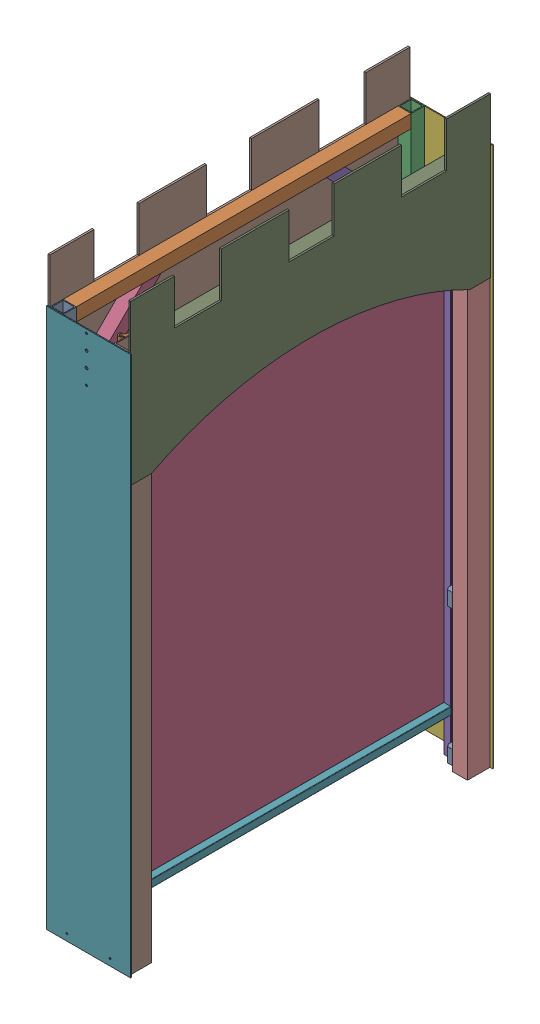
SolidWorks assembly GE-16160_ASM, configuration Default. Lengths in mm.
Overall size (285.75 1981.41 1229.61).
28 component instances, 13 part files, 0 mates.
Components (placement in the parent):
- GE-16161_ASM-1: GE-16161_ASM [Default] at origin size (44.45 1828.8 1223.26)
  - GE-16161-01-1: GE-16161-01 [Default] at origin size (44.45 1828.8 44.45)
  - GE-16161-02-1: GE-16161-02 [Default] at (-22.225 1784.35 -1156.589) size (44.45 44.45 1134.36)
  - GE-16161-01-2: GE-16161-01 [Default] at (0 0 -1178.814) x (-1 0 0) z (0 0 -1) size (44.45 1828.8 44.45)
  - GE-16161-03-1: GE-16161-03 [Default] at (-22.225 1784.35 -246.7314) x (1 0 0) z (0 0.707107 -0.707107) size (44.45 44.45 406.4)
  - GE-16161-03-2: GE-16161-03 [Default] at (-22.225 1559.8436 -1156.589) x (1 0 0) z (0 -0.707107 -0.707107) size (44.45 44.45 406.4)
- GE-16163-1: GE-16163 [Default] at (111.125 914.4 -1201.039) x (0 0 -1) z (0 -1 0) size (3.17 285.75 1828.8)
- GE-16163-2: GE-16163 [Default] at (111.125 914.4 22.225) x (0 0 1) z (0 -1 0) size (3.17 285.75 1828.8)
- GE-16162_ASM-1: GE-16162_ASM [Default] at (219.075 0 -15.875) size (50.8 1828.8 1223.26)
  - GE-16162-01-1: GE-16162-01 [Default] at origin size (50.8 1828.8 76.2)
  - GE-16162-02-1: GE-16162-02 [Default] at (-19.05 1784.35 -1108.964) size (44.45 44.45 1070.86)
  - GE-16162-01-2: GE-16162-01 [Default] at (0 0 -1147.064) x (-1 0 0) z (0 0 -1) size (50.8 1828.8 76.2)
  - GE-16162-03-1: GE-16162-03 [Default] at (-19.05 1559.8436 -38.1) x (1 0 0) z (0 0.707107 -0.707107) size (44.45 44.45 406.4)
  - GE-16162-03-2: GE-16162-03 [Default] at (-19.05 1784.35 -884.4576) x (1 0 0) z (0 -0.707107 -0.707107) size (44.45 44.45 406.4)
- GE-16164-1: GE-16164 [Default] at (193.675 -0.2 -1134.364) x (0 0 1) z (-1 0 0) size (37 1829.02 22)
- GE-16164-2: GE-16164 [Default] at (193.675 1828.8 -44.45) x (0 0 -1) z (-1 0 0) size (37 1829.02 22)
- GE-16165_ASM-1: GE-16165_ASM [Default] at (139.975 1571.625 -17.85) x (-1 0 0) z (0 -1 0) size (68.08 1193.8 1584.33)
  - GE-16166-01-1: GE-16166-01 [Default] at origin size (25.4 1143 25.4)
  - GE-16167-1: GE-16167 [Default] at (15.875 571.5 715.9625) x (0 -1 0) z (-1 0 0) size (1193.8 1457.33 3.18)
  - GE-16166-02-1: GE-16166-02 [Default] at (0 1155.7 -12.7) x (1 0 0) z (0 -1 0) size (25.4 1584.33 25.4)
  - GE-16166-02-2: GE-16166-02 [Default] at (0 -12.7 -12.7) x (-1 0 0) z (0 1 0) size (25.4 1584.33 25.4)
  - GE-16166-01-2: GE-16166-01 [Default] at (0 1143 1431.925) x (1 0 0) z (0 0 -1) size (25.4 1143 25.4)
  - GE-16168-1: GE-16168 [Default] at (-39.7 -2.4 1523.625) x (0 1 0) z (1 0 0) size (44 48 39.5)
  - GE-16168-2: GE-16168 [Default] at (-39.7 -2.4 1063.625) x (0 1 0) z (1 0 0) size (44 48 39.5)
  - GE-16168-3: GE-16168 [Default] at (-39.7 1145.4 1571.625) x (0 -1 0) z (1 0 0) size (44 48 39.5)
  - GE-16168-4: GE-16168 [Default] at (-39.7 1145.4 1111.625) x (0 -1 0) z (1 0 0) size (44 48 39.5)
- GE-16169-1: GE-16169 [Default] at (-28.575 1635.125 -587.375) x (0 0 -1) z (1 0 0) size (1219.2 539.75 6.35)
- GE-16169-2: GE-16169 [Default] at (250.825 1635.125 -587.375) x (0 0 1) z (-1 0 0) size (1219.2 539.75 6.35)
